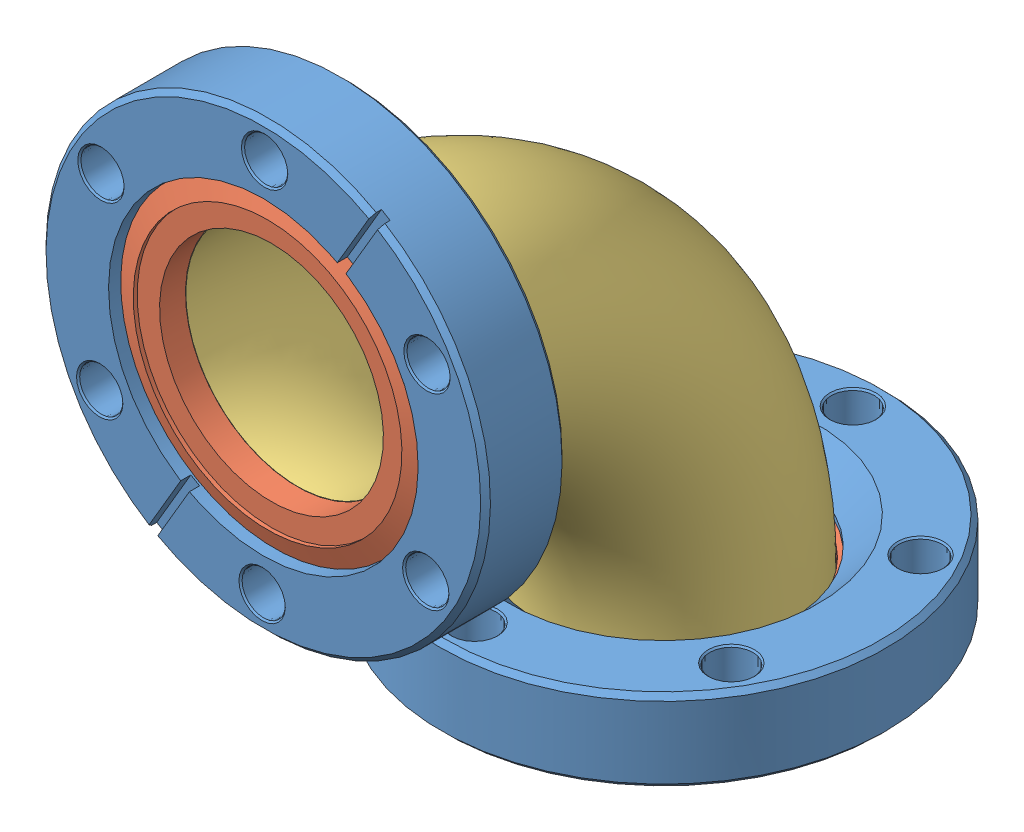
SolidWorks assembly mdc 2.75 elbow, configuration Default. Lengths in mm.
Overall size (94.6 97.36 109.76).
5 component instances, 3 part files, 0 mates.
Components (placement in the parent):
- 915002-1: 915002 [Default] at (0 -49.7586 -54.8386) x (0 -1 0) z (0.495758 0 0.868461) size (12.7 69.34 69.34)
- 915002-2: 915002 [Default] at (0 0 -5.08) x (0 0 1) z (-0.999978 0.006622 0) size (12.7 69.34 69.34)
- 910014-1: 910014 [Default] at origin size (48.06 48.06 6.96)
- 403502-1: 403502 [Default] at (0 -57.15 2.3114) x (0 1 0) z (0 0 1) size (77.27 39.99 77.27)
- 910014-2: 910014 [Default] at (0 -54.8386 -54.8386) x (1 0 0) z (0 -1 0) size (48.06 48.06 6.96)
